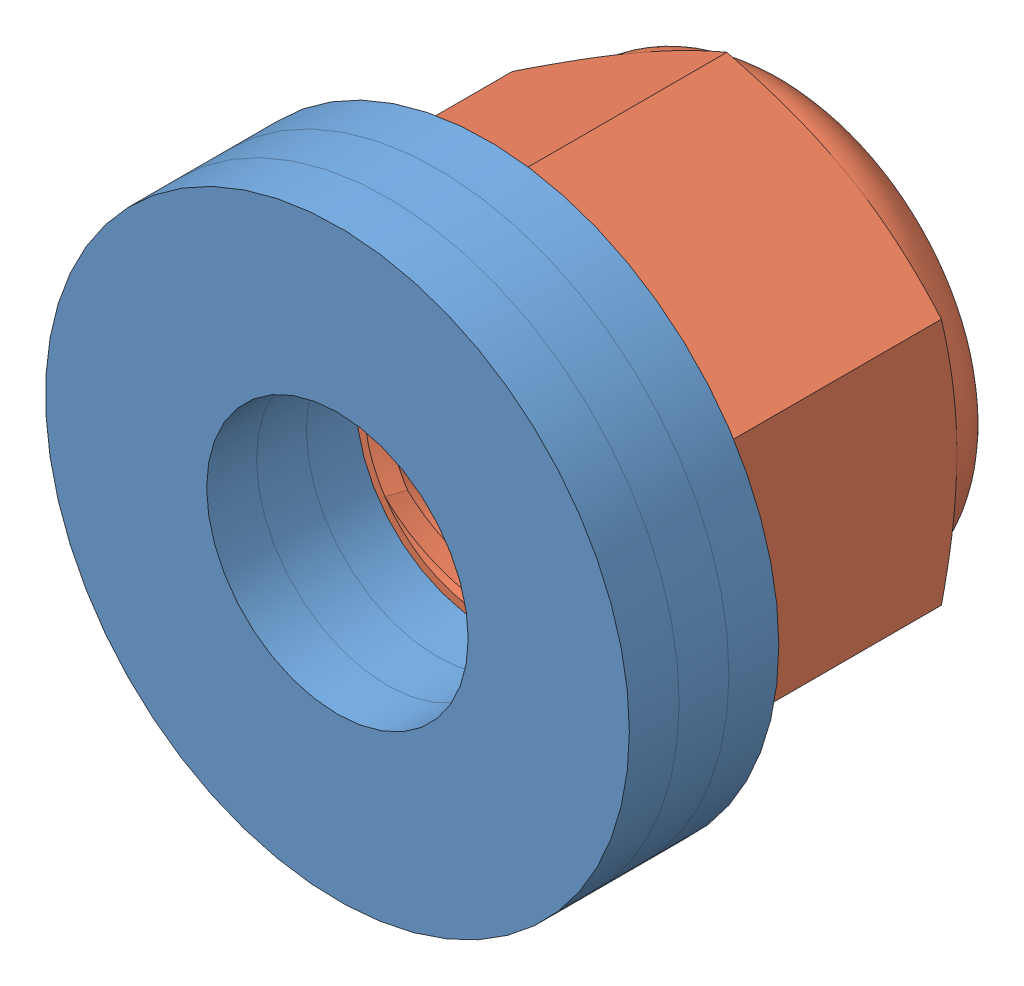
SolidWorks assembly Nut Assy for M4 Flange Bolts, configuration At ESC-WSC flanges. Lengths in mm.
Overall size (9.53 9.53 7.44).
2 component instances, 2 part files, 6 mates.
Components (placement in the parent):
- Washer for M4 flange bolts-1: Washer for M4 flange bolts [At ESC-WSC flanges, 3x MSC 67494203] at origin size (9.53 9.53 2.44)
- Hex Nylock M4 SS316 - McMaster 94205A230-1: Hex Nylock M4 SS316 - McMaster 94205A230 [94205A230] at (0 0 -2.4384) x (1 0 0) z (0 1 0) size (7 5.12 8.08)
Mates (geometry in assembly coordinates):
- Coincident1: coincident aligned: plane of Washer for M4 flange bolts-1 through (0 0 0) normal (0 0 1); plane of assembly through (0 0 0) normal (0 0 1)
- Coincident2: coincident aligned: plane of Washer for M4 flange bolts-1 through (0 0 0) normal (1 0 0); plane of assembly through (0 0 0) normal (1 0 0)
- Coincident3: coincident aligned: plane of Washer for M4 flange bolts-1 through (0 0 0) normal (0 1 0); plane of assembly through (0 0 0) normal (0 1 0)
- Coincident4: coincident anti-aligned: plane of Washer for M4 flange bolts-1 through (0 0 -2.4384) normal (0 0 -1); plane of Hex Nylock M4 SS316 - McMaster 94205A230-1 through (7 0 -2.4384) normal (0 0 1)
- Coincident6: coincident aligned: plane of Hex Nylock M4 SS316 - McMaster 94205A230-1 through (0 0 -2.4384) normal (0 1 0); plane of assembly through (0 0 0) normal (0 1 0)
- Coincident7: coincident aligned: plane of Hex Nylock M4 SS316 - McMaster 94205A230-1; plane of assembly through (0 0 0) normal (1 0 0)
